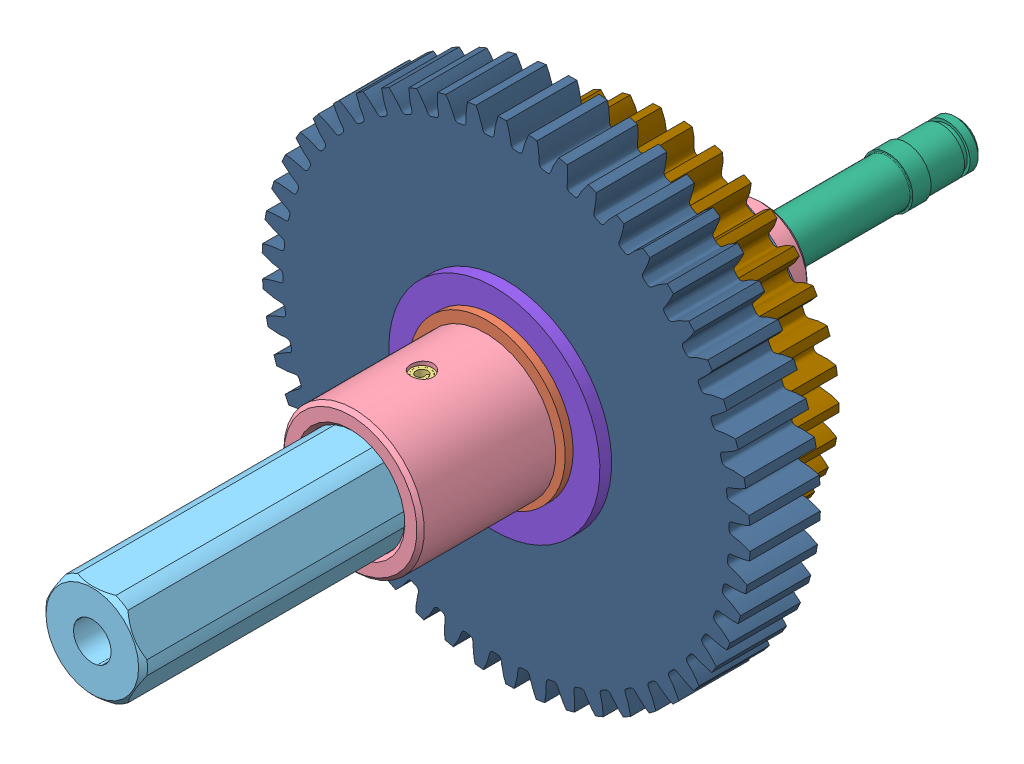
SolidWorks assembly 217-3290-STEP-20140102, configuration Default. Lengths in mm.
Overall size (92.91 92.92 117.22).
19 component instances, 10 part files, 0 mates.
Components (placement in the parent):
- 217-2428-008 Rev2-1: 217-2428-008 Rev2 [Default] at (0 0 10.2679) x (-0.926541 0.376194 0) z (0 0 1) size (31.75 31.75 1.59)
- 217-2428-028 Rev1_97633A250-1: 217-2428-028 Rev1_97633A250 [Default] at (0 0 37.1221) x (0 0 1) z (0.9357 -0.352797 0) size (1.07 23.39 21.18)
- 217-4098-000 Rev2-1: 217-4098-000 Rev2 [Default] x (-1 0 0) z (0 0 1) size (22.23 22.23 117.22)
  - 217-4098-005 Rev1_91612A226-1: 217-4098-005 Rev1_91612A226 [Default] at (0 0 46.2661) x (-0.144757 0 0.989467) z (0 -1 0) size (3.02 3.15 18.22)
  - 217-4098-003 Rev2-1: 217-4098-003 Rev2 [Default] x (1 0 0) z (0 0 -1) size (22.23 22.23 55.94)
  - 217-4098-002 Rev3-1: 217-4098-002 Rev3 [Default] at (0 0 62.9285) x (0 0 1) z (-1 0 0) size (59.88 12.73 14.67)
  - 217-4098-004 Rev1-1: 217-4098-004 Rev1 [Default] at (0 0 14.2494) x (-0.610335 0.792144 0) z (0 0 1) size (11.68 11.68 56)
- 217-2428-007 Rev1-1: 217-2428-007 Rev1 [Default] at (7.809 4.5085 14.2494) x (0.485433 0.3648 -0.794529) z (-0.690104 -0.398066 -0.6044) size (6.35 6.35 6.35)
- 217-2428-007 Rev1-2: 217-2428-007 Rev1 [Default] at (5.4343 3.1375 26.9494) x (0.741485 -0.614816 -0.268704) z (-0.150074 0.23836 -0.959512) size (6.35 6.35 6.35)
- 217-3212-101 Rev1-1: 217-3212-101 Rev1 [Default] at (14.1445 6.5076 45.3224) x (-0.013892 -0.999903 0) z (0 0 -1) size (46.46 46.56 12.7)
  - 217-2428-022 Rev1-1: 217-2428-022 Rev1 [Default] at (6.7035 14.0527 24.6087) size (28.57 28.57 6.1)
  - 217-3212-001 Rev1_34t-1: 217-3212-001 Rev1_34t [Default] at (6.7035 14.0527 27.9107) size (46.46 46.56 11.11)
- 217-3219-101 Rev1-1: 217-3219-101 Rev1 [Default] at (-15.6026 8.1223 56.3187) x (0.799715 0.60038 0) z (0 0 -1) size (66.33 66.39 12.7)
  - 217-2428-022 Rev1-1: 217-2428-022 Rev1 [Default] at (7.6012 15.863 22.905) size (28.57 28.57 6.1)
  - 217-3219-001 Rev1_50t-1: 217-3219-001 Rev1_50t [Default] at (7.6012 15.863 26.207) size (66.33 66.39 11.11)
- 217-2428-007 Rev1-3: 217-2428-007 Rev1 [Default] at (-0.1535 -5.342 26.9494) x (-0.903188 -0.334737 -0.268704) z (0.281462 0.010788 -0.959512) size (6.35 6.35 6.35)
- 217-2428-007 Rev1-4: 217-2428-007 Rev1 [Default] at (-4.703 3.7369 26.9494) x (0.161703 0.949553 -0.268704) z (-0.131389 -0.249147 -0.959512) size (6.35 6.35 6.35)
- 217-2428-007 Rev1-5: 217-2428-007 Rev1 [Default] at (-0.1535 -8.084 14.2494) x (0.073209 -0.602797 -0.794529) z (0.000317 0.796681 -0.6044) size (6.35 6.35 6.35)
- 217-2428-007 Rev1-6: 217-2428-007 Rev1 [Default] at (-7.0777 5.1079 14.2494) x (-0.558642 0.237997 -0.794529) z (0.689788 -0.398615 -0.6044) size (6.35 6.35 6.35)
